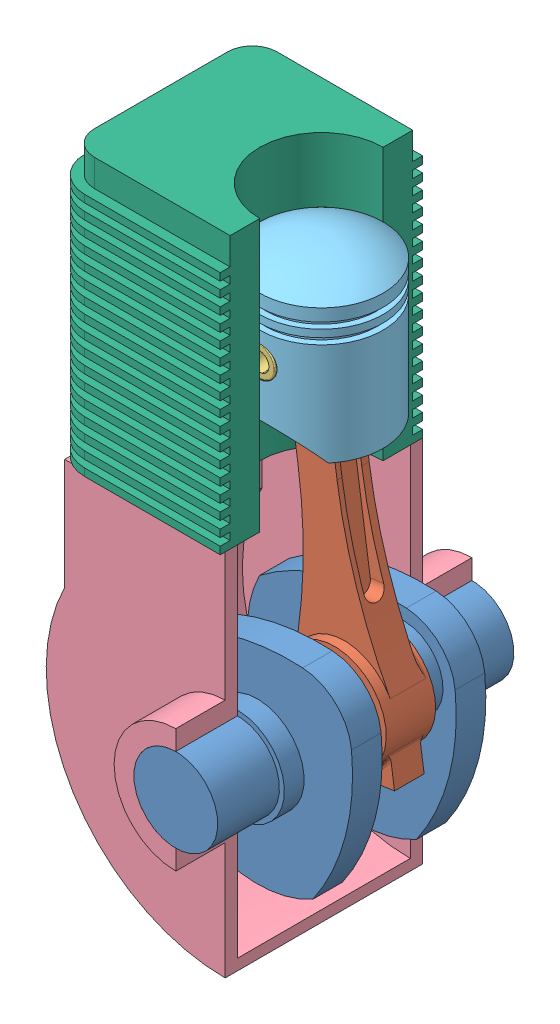
SolidWorks assembly Assem1, configuration Default. Lengths in mm.
Overall size (136.09 259.5 120).
6 component instances, 6 part files, 11 mates.
Components (placement in the parent):
- crank shaft-1: crank shaft [Default] at (172.76 94.6693 8.9553) x (0.722484 -0.691388 0) z (0 0 1) size (88 92 120)
- crankrod-1: crankrod [Default] at (190.0447 112.7314 -23.0447) x (0.989572 0.144039 0) z (0 0 1) size (42 160.15 20)
- gudget pin-1: gudget pin [Default] at (172.76 231.48 -50.0447) x (0 0 1) z (-1 0 0) size (50 12.5 12.5)
- lower case-1: lower case [Default] at (172.76 94.6693 13.9553) size (72.5 149.5 120)
- pistonhead-1: pistonhead [Default] at (172.76 200.98 -25.0447) size (50 64.17 50)
- uppercase-1: uppercase [Default] at (172.76 171.6693 -25.0447) x (0 0 -1) z (1 0 0) size (82 110 69)
Mates (geometry in assembly coordinates):
- Concentric1: concentric: cylinder of assembly; cylinder of assembly; cylinder of crank shaft-1 through (172.76 94.6693 33.9553) axis (0 0 -1) radius 17; cylinder of lower case-1 through (172.76 94.6693 8.9553) axis (0 0 1) radius 17
- Coincident1: coincident: plane of assembly; circle of assembly; plane of crank shaft-1 through (172.76 94.6693 33.9553) normal (0 0 1); circle of lower case-1
- Coincident2: coincident: line of assembly; line of assembly; line of lower case-1 through (172.76 171.6693 -66.0447) axis (-1 0 0); line of uppercase-1 through (117.76 171.6693 -66.0447) axis (1 0 0)
- Coincident3: coincident: line of assembly; line of assembly; line of lower case-1 through (107.76 171.6693 -66.0447) axis (0 0 1); line of uppercase-1 through (103.76 171.6693 1.9553) axis (0 0 -1)
- Coincident4: coincident: line of assembly; line of assembly; line of lower case-1 through (172.76 171.6693 8.9553) axis (0 0 1); line of uppercase-1 through (172.76 171.6693 15.9553) axis (0 0 -1)
- Coincident5: coincident: circle of assembly; circle of assembly; circle of crankrod-1; circle of pistonhead-1
- Concentric4: concentric: cylinder of assembly; cylinder of assembly; cylinder of gudget pin-1 through (172.76 231.48 -0.0447) axis (0 0 -1) radius 6.25; cylinder of pistonhead-1 through (172.76 231.48 -50.0447) axis (0 0 1) radius 6.25
- Tangent3: tangent: torus of assembly; cylinder of assembly; torus of gudget pin-1; cylinder of pistonhead-1 through (172.76 231.48 -50.0447) axis (0 0 1) radius 6.25
- Tangent4: tangent: plane of assembly; cylinder of assembly; plane of gudget pin-1 through (172.76 231.48 -0.0447) normal (0 0 1); cylinder of pistonhead-1 through (172.76 263.48 -25.0447) axis (0 1 0) radius 25
- Concentric5: concentric: cylinder of assembly; cylinder of assembly; cylinder of pistonhead-1 through (172.76 263.48 -25.0447) axis (0 1 0) radius 25; cylinder of uppercase-1 through (172.76 281.6693 -25.0447) axis (0 -1 0) radius 25
- Concentric6: concentric: cylinder of assembly; cylinder of assembly; cylinder of crank shaft-1 through (190.0447 112.7314 -26.0447) axis (0 0 1) radius 16; cylinder of crankrod-1 through (190.0447 112.7314 -13.0447) axis (0 0 -1) radius 16
